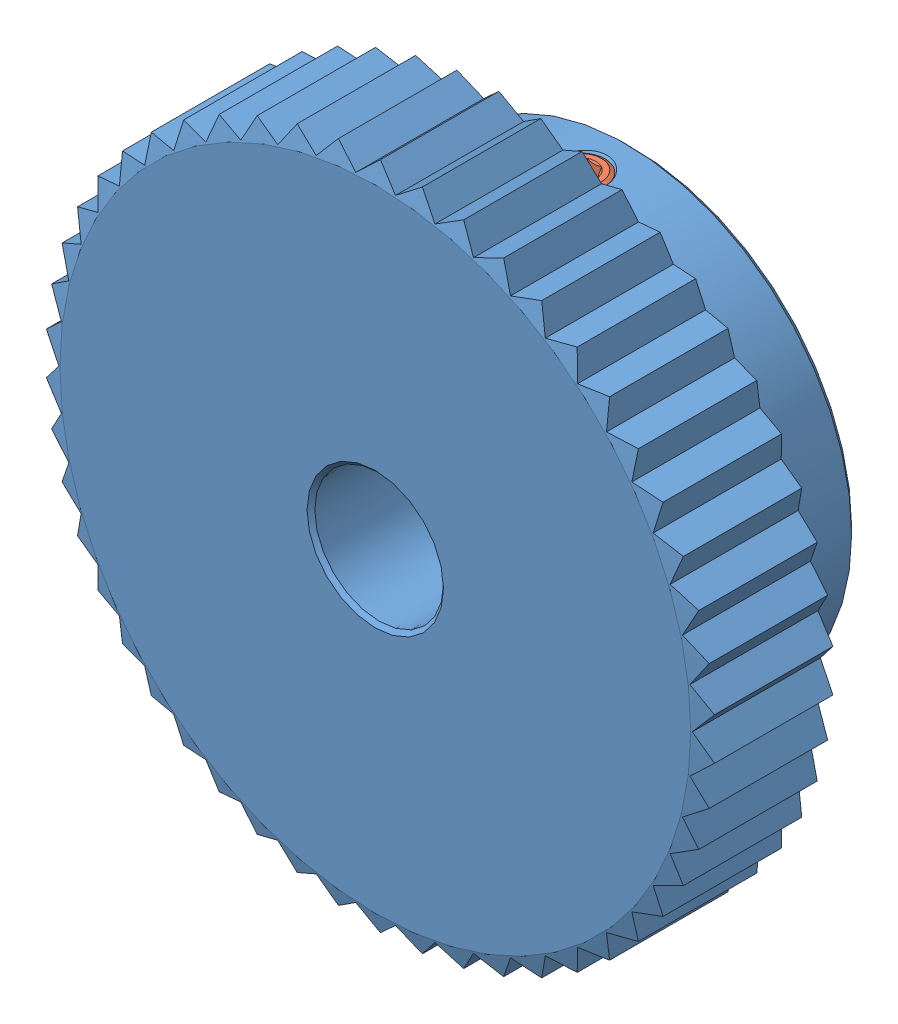
SolidWorks assembly Assem1, configuration Default. Lengths in mm.
Overall size (51.9 52 22).
3 component instances, 2 part files, 0 mates.
Components (placement in the parent):
- GEABP1_0_50_10_B_10_KC90_b-1: GEABP1_0_50_10_B_10_KC90_b [Default] x (-1 0 0) z (0 0 -1) size (51.9 52 20)
- Hexagon_socket_set_screw_with_flat_point_DIN_913___M4x12-1: Hexagon_socket_set_screw_with_flat_point_DIN_913___M4x12 [Default] at (0 17.5 -16) x (0 -1 0) z (1 0 0) size (12 4 4)
- Hexagon_socket_set_screw_with_flat_point_DIN_913___M4x12-2: Hexagon_socket_set_screw_with_flat_point_DIN_913___M4x12 [Default] at (-17.5 0 -16) x (1 0 0) z (0 0 -1) size (12 4 4)
